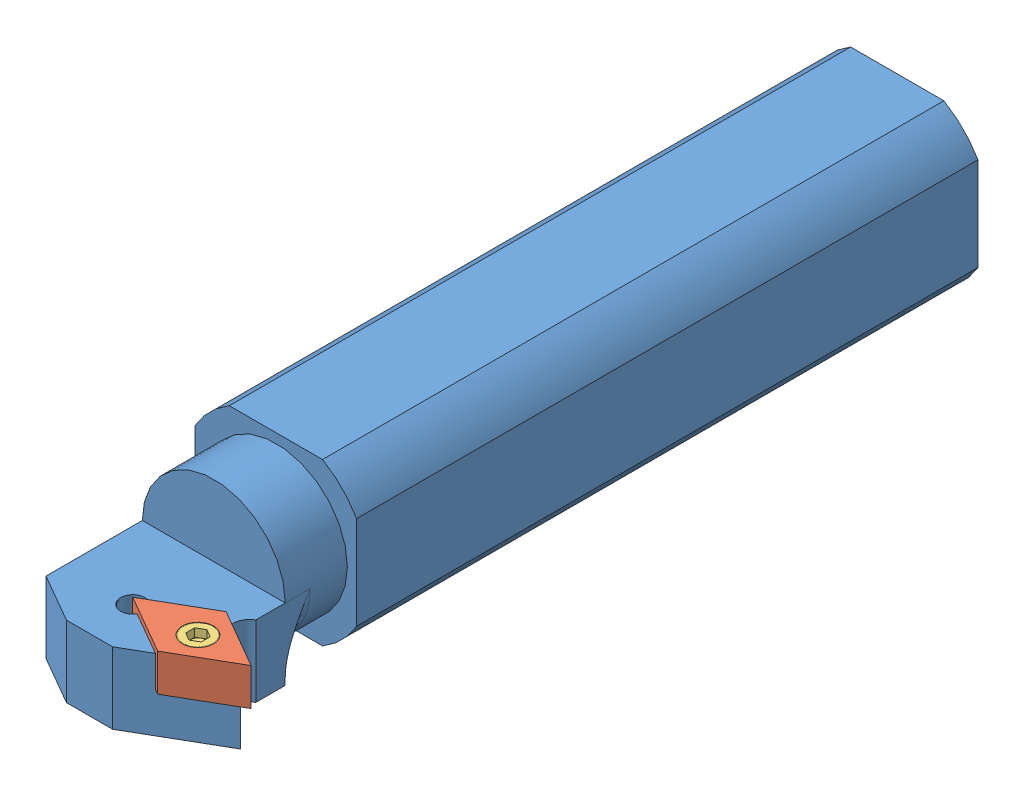
SolidWorks assembly 镗刀, configuration 默认. Lengths in mm.
Overall size (31.47 25.98 130).
3 component instances, 3 part files, 5 mates.
Components (placement in the parent):
- 镗刀刀柄-1: 镗刀刀柄 [默认] at (-3.2581 2.8626 -65) size (29.74 25.98 130)
- 镗刀刀片-2: 镗刀刀片 [默认] at (5.6946 -2.1374 57.4707) x (1 0 0) z (0 1 0) size (19.05 11 6)
- hexagon socket head cap screws gb2-1: hexagon socket head cap screws gb2 [GB_FASTENER_SCREWS_HSHCS M3X5-N] at (6.6683 3.8626 57.4707) x (0 -1 0) z (0 0 1) size (8 5.5 5.5)
Mates (geometry in assembly coordinates):
- 重合4: coincident anti-aligned: plane of 镗刀刀柄-1 through (-3.8317 -2.1374 57.4707) normal (0 1 0); plane of 镗刀刀片-2 through (5.6946 -2.1374 57.4707) normal (0 -1 0)
- 重合5: coincident anti-aligned: plane of 镗刀刀柄-1 through (4.8286 -2.1374 62.4707) normal (0.5 0 -0.866025); plane of 镗刀刀片-2 through (-3.8317 3.8626 57.4707) normal (-0.5 0 0.866025)
- 重合6: coincident anti-aligned: plane of 镗刀刀柄-1 through (-2.156 -2.1374 56.5033) normal (0.5 0 0.866025); plane of 镗刀刀片-2 through (5.6946 3.8626 51.9707) normal (-0.5 0 -0.866025)
- 同心1: concentric aligned: cylinder of 镗刀刀片-2 through (6.6683 3.8626 57.4707) axis (0 1 0) radius 2.5; cylinder of hexagon socket head cap screws gb-1 through (6.6683 -4.1374 57.4707) axis (0 1 0) radius 1.5
- 重合7: coincident anti-aligned: plane of 镗刀刀片-2 through (8.1683 0.8626 57.4707) normal (0 1 0); plane of hexagon socket head cap screws gb-1 through (6.6683 0.8626 57.4707) normal (0 -1 0)
